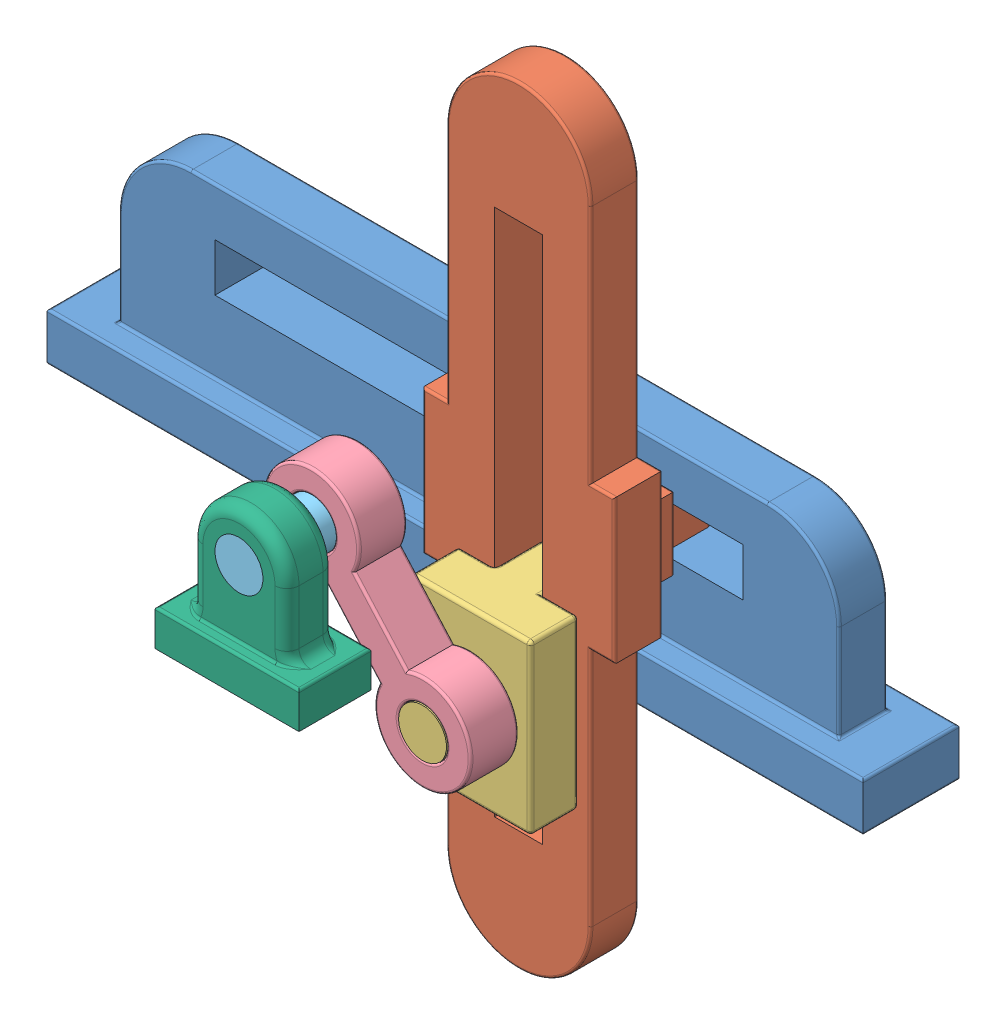
SolidWorks assembly Final Assembly, configuration Default. Lengths in mm.
Overall size (340 320 135).
6 component instances, 6 part files, 12 mates.
Components (placement in the parent):
- 6.Slider Body-1: 6.Slider Body [Default] at (33.4493 200.8244 294.4052) size (340 90 40)
- 4.Slider-1: 4.Slider [Default] at (189.9295 340.8244 344.4052) x (-1 0 0) z (0 0 -1) size (80 320 50)
- 3.connector-1: 3.connector [Default] at (164.9295 156.1149 364.4052) size (50 70 60)
- 2.connecting rod-1: 2.connecting rod [Default] at (143.4493 208.4559 374.4052) x (0.747729 0.664004 0) z (0 0 1) size (40 110 20)
- 5.Connecting-1: 5.Connecting [Default] at (143.4493 208.4559 364.4052) x (0.956467 -0.29184 0) z (0 0 1) size (20 20 50)
- 1.Rotor-2: 1.Rotor [Default] at (113.4493 180.8244 419.4052) x (1 0 0) z (0 -1 0) size (60 30 62.63)
Mates (geometry in assembly coordinates):
- Coincident1: coincident anti-aligned: plane of 6.Slider Body-1 through (33.4493 220.8244 314.4052) normal (0 -1 0); plane of 4.Slider-1 through (159.9295 220.8244 294.4052) normal (0 1 0)
- Coincident2: coincident anti-aligned: plane of 6.Slider Body-1 through (-26.5507 150.8244 324.4052) normal (0 0 1); plane of 4.Slider-1 through (189.9295 340.8244 324.4052) normal (0 0 -1)
- Coincident3: coincident anti-aligned: plane of 4.Slider-1 through (199.9295 320.8244 324.4052) normal (-1 0 0); plane of 3.connector-1 through (199.9295 191.1149 344.4052) normal (1 0 0)
- Coincident4: coincident anti-aligned: plane of 4.Slider-1 through (189.9295 340.8244 344.4052) normal (0 0 1); plane of 3.connector-1 through (214.9295 191.1149 344.4052) normal (0 0 -1)
- Concentric1: concentric anti-aligned: cylinder of 3.connector-1 through (189.9295 156.1149 384.4052) axis (0 0 -1) radius 10; circle of 2.connecting rod-1
- Coincident6: coincident aligned: plane of 3.connector-1 through (189.9295 156.1149 384.4052) normal (0 0 1); plane of 2.connecting rod-1 through (143.4493 208.4559 384.4052) normal (0 0 1)
- Concentric2: concentric aligned: cylinder of 2.connecting rod-1 through (143.4493 208.4559 384.4052) axis (0 0 -1) radius 10; cylinder of 5.Connecting-1 through (143.4493 208.4559 414.4052) axis (0 0 -1) radius 10
- Coincident8: coincident aligned: plane of 2.connecting rod-1 through (143.4493 208.4559 364.4052) normal (0 0 -1); plane of 5.Connecting-1 through (143.4493 208.4559 364.4052) normal (0 0 -1)
- Coincident17: coincident anti-aligned: plane of 6.Slider Body-1 through (33.4493 165.8244 294.4052) normal (0 1 0); plane of 1.Rotor-2 through (113.4493 165.8244 419.4052) normal (0 -1 0)
- Coincident18: coincident anti-aligned: line of 6.Slider Body-1 through (143.4493 165.8244 314.4052) axis (0 0 1); line of 1.Rotor-2 through (143.4493 165.8244 419.4052) axis (0 0 -1)
- Concentric4: concentric aligned: cylinder of 5.Connecting-1 through (143.4493 208.4559 414.4052) axis (0 0 -1) radius 10; cylinder of 1.Rotor-2 through (143.4493 208.4559 414.4052) axis (0 0 -1) radius 10
- Coincident19: coincident aligned: plane of 5.Connecting-1 through (143.4493 208.4559 414.4052) normal (0 0 1); plane of 1.Rotor-2 through (143.4493 208.4559 414.4052) normal (0 0 1)
